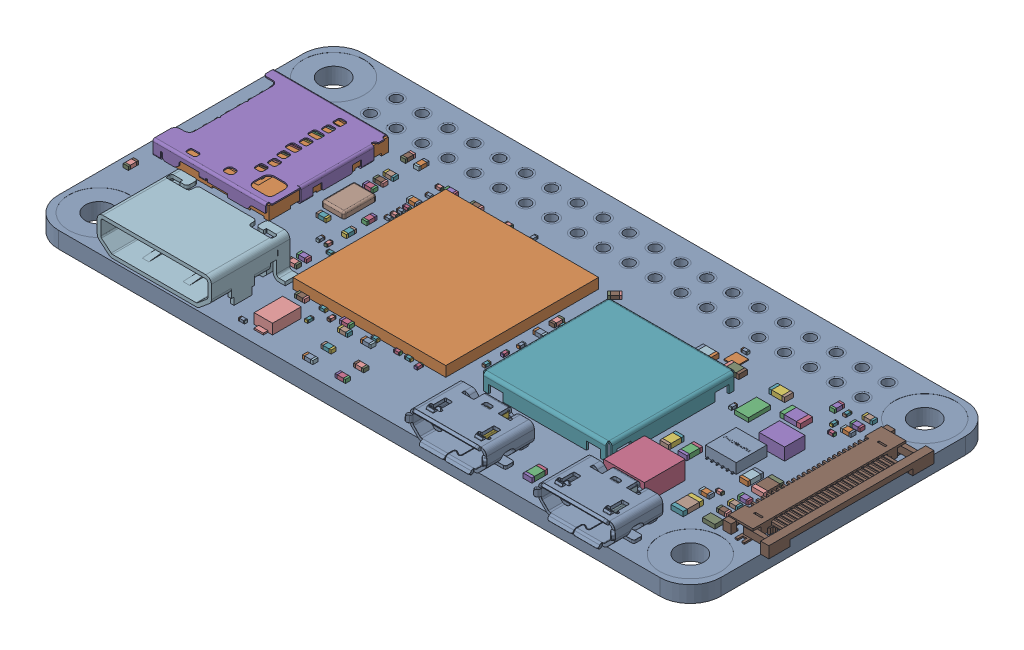
SolidWorks assembly Raspberry Pi Zero 2 W, configuration 默认. Lengths in mm.
Overall size (65.8 5.05 30.58).
93 component instances, 21 part files, 0 mates.
Components (placement in the parent):
- PCB, Raspberry Pi Zero 2 W-1: PCB, Raspberry Pi Zero 2 W [默认] at origin size (65 1.6 30)
- RP3A0-AU 2105 201221C, Raspberry Pi Zero 2 W-1: RP3A0-AU 2105 201221C, Raspberry Pi Zero 2 W [默认] at (-5.5 0.8 1) size (15 1 15)
- MicroUSB Port, Raspberry Pi Zero 2 W-1: MicroUSB Port, Raspberry Pi Zero 2 W [默认] at (8.9 0.8 13) size (7.99 2.94 5.43)
- SD Card Slot, Raspberry Pi Zero 2 W-1: SD Card Slot, Raspberry Pi Zero 2 W [默认] at (-25.5 0.8 -2) x (0 0 1) z (-1 0 0) size (11.95 1.45 11.4)
- Wireless Module Cover, Raspberry Pi Zero 2 W-1: Wireless Module Cover, Raspberry Pi Zero 2 W [默认] at (11 0.8 1.5) size (12.6 1.6 12.6)
- Crystal Resonator, Raspberry Pi Zero 2 W-1: Crystal Resonator, Raspberry Pi Zero 2 W [默认] at (-17.5 0.8 -1.5) size (2.2 0.6 3.2)
- LED, Raspberry Pi Zero 2 W-1: LED, Raspberry Pi Zero 2 W [默认] at (27.5 0.8 7.8) size (1.2 0.4 0.8)
- Diode, Schottky, Raspberry Pi Zero 2 W-1: Diode, Schottky, Raspberry Pi Zero 2 W [默认] at (-11 0.8 12) size (1.8 1 3.7)
- 54548-2271, 22 Pin FPC Connector, Raspberry Pi Zero 2 W-1: 54548-2271, 22 Pin FPC Connector, Raspberry Pi Zero 2 W [默认] at (28.75 0.82 0) x (0 0 -1) z (1 0 0) size (16.2 1.2 5)
- Mini HDMI Receptacle Port, Raspberry Pi Zero 2 W-1: Mini HDMI Receptacle Port, Raspberry Pi Zero 2 W [默认] at (-20.1 2.65 15) size (12.9 4.05 7.7)
- PAM2306AYPKE, Switching Voltage Regulators Dual PWM Step-Down 40uA 1A_ 1.5MHz, Raspberry Pi Zero 2 W-1: PAM2306AYPKE, Switching Voltage Regulators Dual PWM Step-Down 40uA 1A_ 1.5MHz, Raspberry Pi Zero 2 W [默认] at (23 0.8 1) x (0 0 1) z (-1 0 0) size (3.4 1 3)
- RT9081A-1BGQZA, Fixed LDO Voltage Regulator, 0.8V-5.5Vin, 140mV drop,_ 1.25Vout, 0.5Aout, Raspberry Pi Zero 2 W_default-1: RT9081A-1BGQZA, Fixed LDO Voltage Regulator, 0.8V-5.5Vin, 140mV drop,_ 1.25Vout, 0.5Aout, Raspberry Pi Zero 2 W_default [默认] at (14.8 0.8 -7.2) size (1.2 0.1 1.2)
- RT8088AWSC, IC Reg Buck Prog 3A Sync 15WLCSP, Raspberry Pi Zero 2 W_d_efault-1: RT8088AWSC, IC Reg Buck Prog 3A Sync 15WLCSP, Raspberry Pi Zero 2 W_d_efault [默认] at (20 0.8 -3.6) size (1.36 0.4 2.16)
- SMD Inductor, Configurable, Raspberry Pi Zero 2 W_L1-1: SMD Inductor, Configurable, Raspberry Pi Zero 2 W_L1 [默认] at (20.5 0.8 7.5) size (4 1.8 4)
- SMD Inductor, Configurable, Raspberry Pi Zero 2 W_L2-1: SMD Inductor, Configurable, Raspberry Pi Zero 2 W_L2 [默认] at (24.5 0.8 -2) size (2.5 1.2 2)
- SMD Capacitor, Configurable, Raspberry Pi Zero 2 W_C1-1: SMD Capacitor, Configurable, Raspberry Pi Zero 2 W_C1 [默认] at (24.9 0.8 7.7) size (1.2 0.45 2)
- MicroUSB Port, Raspberry Pi Zero 2 W-2: MicroUSB Port, Raspberry Pi Zero 2 W [默认] at (21.5 0.8 13) size (7.99 2.94 5.43)
- SMD Capacitor, Configurable, Raspberry Pi Zero 2 W_C3-1: SMD Capacitor, Configurable, Raspberry Pi Zero 2 W_C3 [默认] at (20.5 0.8 3) size (0.85 0.45 1.55)
- SMD Capacitor, Configurable, Raspberry Pi Zero 2 W_C3-2: SMD Capacitor, Configurable, Raspberry Pi Zero 2 W_C3 [默认] at (18.7 0.8 3) size (0.85 0.45 1.55)
- SMD Capacitor, Configurable, Raspberry Pi Zero 2 W_C1-2: SMD Capacitor, Configurable, Raspberry Pi Zero 2 W_C1 [默认] at (27.3 0.8 2.2) size (1.2 0.45 2)
- SMD Capacitor, Configurable, Raspberry Pi Zero 2 W_C3-3: SMD Capacitor, Configurable, Raspberry Pi Zero 2 W_C3 [默认] at (25.7 0.8 2.2) size (0.85 0.45 1.55)
- SMD Capacitor, Configurable, Raspberry Pi Zero 2 W_C1-3: SMD Capacitor, Configurable, Raspberry Pi Zero 2 W_C1 [默认] at (22.8 0.8 -5.1) x (0 0 -1) z (1 0 0) size (1.2 0.45 2)
- SMD Capacitor, Configurable, Raspberry Pi Zero 2 W_C3-4: SMD Capacitor, Configurable, Raspberry Pi Zero 2 W_C3 [默认] at (20 0.8 -6.4) x (0 0 -1) z (1 0 0) size (0.85 0.45 1.55)
- SMD Capacitor, Configurable, Raspberry Pi Zero 2 W_C3-5: SMD Capacitor, Configurable, Raspberry Pi Zero 2 W_C3 [默认] at (15.8 0.8 -6.1) x (0 0 -1) z (1 0 0) size (0.85 0.45 1.55)
- SMD Capacitor, Configurable, Raspberry Pi Zero 2 W_C3-6: SMD Capacitor, Configurable, Raspberry Pi Zero 2 W_C3 [默认] at (13 0.8 -6.1) x (0 0 -1) z (1 0 0) size (0.85 0.45 1.55)
- SMD Capacitor, Configurable, Raspberry Pi Zero 2 W_C3-7: SMD Capacitor, Configurable, Raspberry Pi Zero 2 W_C3 [默认] at (14.8 0.8 12.5) size (0.85 0.45 1.55)
- SMD Capacitor, Configurable, Raspberry Pi Zero 2 W_C2-1: SMD Capacitor, Configurable, Raspberry Pi Zero 2 W_C2 [默认] at (-9.5 0.8 10.4) size (0.3 0.25 0.6)
- SMD Capacitor, Configurable, Raspberry Pi Zero 2 W_C10-1: SMD Capacitor, Configurable, Raspberry Pi Zero 2 W_C10 [默认] at (-31.4 0.8 6) size (0.5 0.35 1)
- SMD Capacitor, Configurable, Raspberry Pi Zero 2 W_C10-2: SMD Capacitor, Configurable, Raspberry Pi Zero 2 W_C10 [默认] at (-6.1 0.8 13.7) x (0 0 -1) z (1 0 0) size (0.5 0.35 1)
- SMD Capacitor, Configurable, Raspberry Pi Zero 2 W_C10-3: SMD Capacitor, Configurable, Raspberry Pi Zero 2 W_C10 [默认] at (-2.9 0.8 13.7) x (0 0 -1) z (1 0 0) size (0.5 0.35 1)
- SMD Capacitor, Configurable, Raspberry Pi Zero 2 W_C10-4: SMD Capacitor, Configurable, Raspberry Pi Zero 2 W_C10 [默认] at (-6.1 0.8 11.9) x (0 0 -1) z (1 0 0) size (0.5 0.35 1)
- SMD Capacitor, Configurable, Raspberry Pi Zero 2 W_C10-5: SMD Capacitor, Configurable, Raspberry Pi Zero 2 W_C10 [默认] at (-2.9 0.8 11.9) x (0 0 -1) z (1 0 0) size (0.5 0.35 1)
- SMD Capacitor, Configurable, Raspberry Pi Zero 2 W_C10-6: SMD Capacitor, Configurable, Raspberry Pi Zero 2 W_C10 [默认] at (-4.6 0.8 9.5) x (0 0 -1) z (1 0 0) size (0.5 0.35 1)
- SMD Capacitor, Configurable, Raspberry Pi Zero 2 W_C10-7: SMD Capacitor, Configurable, Raspberry Pi Zero 2 W_C10 [默认] at (-7.3 0.8 8.9) x (0 0 -1) z (1 0 0) size (0.5 0.35 1)
- SMD Capacitor, Configurable, Raspberry Pi Zero 2 W_C2-2: SMD Capacitor, Configurable, Raspberry Pi Zero 2 W_C2 [默认] at (-4.6 0.8 8.8) x (0 0 -1) z (1 0 0) size (0.3 0.25 0.6)
- SMD Capacitor, Configurable, Raspberry Pi Zero 2 W_C10-8: SMD Capacitor, Configurable, Raspberry Pi Zero 2 W_C10 [默认] at (2.9 0.8 -1.5) x (-1 0 0) z (0 0 -1) size (0.5 0.35 1)
- SMD Capacitor, Configurable, Raspberry Pi Zero 2 W_C10-9: SMD Capacitor, Configurable, Raspberry Pi Zero 2 W_C10 [默认] at (3.1 0.8 0.3) x (0 0 -1) z (1 0 0) size (0.5 0.35 1)
- SMD Capacitor, Configurable, Raspberry Pi Zero 2 W_C2-3: SMD Capacitor, Configurable, Raspberry Pi Zero 2 W_C2 [默认] at (-2.4 0.8 8.8) x (0 0 -1) z (1 0 0) size (0.3 0.25 0.6)
- SMD Capacitor, Configurable, Raspberry Pi Zero 2 W_C2-4: SMD Capacitor, Configurable, Raspberry Pi Zero 2 W_C2 [默认] at (-9.7 0.8 8.8) x (0 0 -1) z (1 0 0) size (0.3 0.25 0.6)
- SMD Capacitor, Configurable, Raspberry Pi Zero 2 W_C2-5: SMD Capacitor, Configurable, Raspberry Pi Zero 2 W_C2 [默认] at (-8.5 0.8 9.2) x (-1 0 0) z (0 0 -1) size (0.3 0.25 0.6)
- SMD Capacitor, Configurable, Raspberry Pi Zero 2 W_C2-6: SMD Capacitor, Configurable, Raspberry Pi Zero 2 W_C2 [默认] at (3.1 0.8 2.2) x (-1 0 0) z (0 0 -1) size (0.3 0.25 0.6)
- SMD Capacitor, Configurable, Raspberry Pi Zero 2 W_C2-7: SMD Capacitor, Configurable, Raspberry Pi Zero 2 W_C2 [默认] at (3 0.8 3.7) x (-1 0 0) z (0 0 -1) size (0.3 0.25 0.6)
- SMD Capacitor, Configurable, Raspberry Pi Zero 2 W_C2-8: SMD Capacitor, Configurable, Raspberry Pi Zero 2 W_C2 [默认] at (3 0.8 5.5) x (-1 0 0) z (0 0 -1) size (0.3 0.25 0.6)
- SMD Capacitor, Configurable, Raspberry Pi Zero 2 W_C10-10: SMD Capacitor, Configurable, Raspberry Pi Zero 2 W_C10 [默认] at (-27.8 0.8 7.8) x (0 0 -1) z (1 0 0) size (0.5 0.35 1)
- SMD Capacitor, Configurable, Raspberry Pi Zero 2 W_C2-9: SMD Capacitor, Configurable, Raspberry Pi Zero 2 W_C2 [默认] at (-12.7 0.8 13.7) x (0 0 -1) z (1 0 0) size (0.3 0.25 0.6)
- SMD Capacitor, Configurable, Raspberry Pi Zero 2 W_C10-11: SMD Capacitor, Configurable, Raspberry Pi Zero 2 W_C10 [默认] at (-17.7 0.8 -3.8) x (0 0 -1) z (1 0 0) size (0.5 0.35 1)
- SMD Capacitor, Configurable, Raspberry Pi Zero 2 W_C10-12: SMD Capacitor, Configurable, Raspberry Pi Zero 2 W_C10 [默认] at (-17.5 0.8 1) x (0 0 -1) z (1 0 0) size (0.5 0.35 1)
- SMD Capacitor, Configurable, Raspberry Pi Zero 2 W_C2-10: SMD Capacitor, Configurable, Raspberry Pi Zero 2 W_C2 [默认] at (-7.7 0.8 -7.4) x (0 0 -1) z (1 0 0) size (0.3 0.25 0.6)
- SMD Capacitor, Configurable, Raspberry Pi Zero 2 W_C2-11: SMD Capacitor, Configurable, Raspberry Pi Zero 2 W_C2 [默认] at (-5.4 0.8 -7.5) x (-1 0 0) z (0 0 -1) size (0.3 0.25 0.6)
- SMD Capacitor, Configurable, Raspberry Pi Zero 2 W_C2-12: SMD Capacitor, Configurable, Raspberry Pi Zero 2 W_C2 [默认] at (-0.15 0.8 9) x (-1 0 0) z (0 0 -1) size (0.3 0.25 0.6)
- SMD Capacitor, Configurable, Raspberry Pi Zero 2 W_C2-13: SMD Capacitor, Configurable, Raspberry Pi Zero 2 W_C2 [默认] at (-1.3 0.8 8.8) x (0 0 -1) z (1 0 0) size (0.3 0.25 0.6)
- SMD Capacitor, Configurable, Raspberry Pi Zero 2 W_C10-13: SMD Capacitor, Configurable, Raspberry Pi Zero 2 W_C10 [默认] at (-15 0.8 6.4) x (0 0 -1) z (1 0 0) size (0.5 0.35 1)
- SMD Capacitor, Configurable, Raspberry Pi Zero 2 W_C2-14: SMD Capacitor, Configurable, Raspberry Pi Zero 2 W_C2 [默认] at (-14.2 0.8 -2.1) x (0 0 -1) z (1 0 0) size (0.3 0.25 0.6)
- SMD Capacitor, Configurable, Raspberry Pi Zero 2 W_C10-14: SMD Capacitor, Configurable, Raspberry Pi Zero 2 W_C10 [默认] at (-15 0.8 -1) size (0.5 0.35 1)
- SMD Capacitor, Configurable, Raspberry Pi Zero 2 W_C10-15: SMD Capacitor, Configurable, Raspberry Pi Zero 2 W_C10 [默认] at (-14.9 0.8 1.1) size (0.5 0.35 1)
- SMD Capacitor, Configurable, Raspberry Pi Zero 2 W_C2-15: SMD Capacitor, Configurable, Raspberry Pi Zero 2 W_C2 [默认] at (-14.3 0.8 -7.2) x (0 0 -1) z (1 0 0) size (0.3 0.25 0.6)
- SMD Capacitor, Configurable, Raspberry Pi Zero 2 W_C2-16: SMD Capacitor, Configurable, Raspberry Pi Zero 2 W_C2 [默认] at (-14.1 0.8 -6) x (0 0 -1) z (1 0 0) size (0.3 0.25 0.6)
- SMD Capacitor, Configurable, Raspberry Pi Zero 2 W_C2-17: SMD Capacitor, Configurable, Raspberry Pi Zero 2 W_C2 [默认] at (-13.3 0.8 1.7) size (0.3 0.25 0.6)
- SMD Capacitor, Configurable, Raspberry Pi Zero 2 W_C2-18: SMD Capacitor, Configurable, Raspberry Pi Zero 2 W_C2 [默认] at (-13.3 0.8 -0.9) size (0.3 0.25 0.6)
- SMD Capacitor, Configurable, Raspberry Pi Zero 2 W_C2-19: SMD Capacitor, Configurable, Raspberry Pi Zero 2 W_C2 [默认] at (-14.2 0.8 -2.7) x (0 0 -1) z (1 0 0) size (0.3 0.25 0.6)
- SMD Capacitor, Configurable, Raspberry Pi Zero 2 W_C2-20: SMD Capacitor, Configurable, Raspberry Pi Zero 2 W_C2 [默认] at (-14.2 0.8 -3.3) x (0 0 -1) z (1 0 0) size (0.3 0.25 0.6)
- SMD Capacitor, Configurable, Raspberry Pi Zero 2 W_C2-21: SMD Capacitor, Configurable, Raspberry Pi Zero 2 W_C2 [默认] at (-14.2 0.8 -3.9) x (0 0 -1) z (1 0 0) size (0.3 0.25 0.6)
- SMD Capacitor, Configurable, Raspberry Pi Zero 2 W_C2-22: SMD Capacitor, Configurable, Raspberry Pi Zero 2 W_C2 [默认] at (-14.1 0.8 3.7) x (0 0 -1) z (1 0 0) size (0.3 0.25 0.6)
- SMD Capacitor, Configurable, Raspberry Pi Zero 2 W_C2-23: SMD Capacitor, Configurable, Raspberry Pi Zero 2 W_C2 [默认] at (-15 0.8 3) size (0.3 0.25 0.6)
- SMD Capacitor, Configurable, Raspberry Pi Zero 2 W_C2-24: SMD Capacitor, Configurable, Raspberry Pi Zero 2 W_C2 [默认] at (-15.8 0.8 3) size (0.3 0.25 0.6)
- SMD Capacitor, Configurable, Raspberry Pi Zero 2 W_C2-25: SMD Capacitor, Configurable, Raspberry Pi Zero 2 W_C2 [默认] at (25.8 0.8 -5.6) x (0 0 -1) z (1 0 0) size (0.3 0.25 0.6)
- SMD Capacitor, Configurable, Raspberry Pi Zero 2 W_C2-26: SMD Capacitor, Configurable, Raspberry Pi Zero 2 W_C2 [默认] at (25.1 0.8 -6.5) size (0.3 0.25 0.6)
- SMD Capacitor, Configurable, Raspberry Pi Zero 2 W_C2-27: SMD Capacitor, Configurable, Raspberry Pi Zero 2 W_C2 [默认] at (25.3 0.8 4.9) x (0 0 -1) z (1 0 0) size (0.3 0.25 0.6)
- SMD Capacitor, Configurable, Raspberry Pi Zero 2 W_C2-28: SMD Capacitor, Configurable, Raspberry Pi Zero 2 W_C2 [默认] at (18.7 0.8 -3) size (0.3 0.25 0.6)
- SMD Capacitor, Configurable, Raspberry Pi Zero 2 W_C2-29: SMD Capacitor, Configurable, Raspberry Pi Zero 2 W_C2 [默认] at (6.9269 0.8 8.9) x (0 0 -1) z (1 0 0) size (0.3 0.25 0.6)
- SMD Capacitor, Configurable, Raspberry Pi Zero 2 W_C2-30: SMD Capacitor, Configurable, Raspberry Pi Zero 2 W_C2 [默认] at (3.5 0.8 -1.5) x (-1 0 0) z (0 0 -1) size (0.3 0.25 0.6)
- SMD Resistor, Configurable, Raspberry Pi Zero 2 W_R1-1: SMD Resistor, Configurable, Raspberry Pi Zero 2 W_R1 [默认] at (-18.4 0.8 -8.2) size (0.5 0.35 1)
- SMD Resistor, Configurable, Raspberry Pi Zero 2 W_R1-2: SMD Resistor, Configurable, Raspberry Pi Zero 2 W_R1 [默认] at (-17.1 0.8 -8.2) size (0.5 0.35 1)
- SMD Resistor, Configurable, Raspberry Pi Zero 2 W_R1-3: SMD Resistor, Configurable, Raspberry Pi Zero 2 W_R1 [默认] at (23.9 0.8 -8) size (0.5 0.35 1)
- SMD Resistor, Configurable, Raspberry Pi Zero 2 W_R12-1: SMD Resistor, Configurable, Raspberry Pi Zero 2 W_R12 [默认] at (24.9 0.8 -8) size (0.3 0.23 0.6)
- SMD Resistor, Configurable, Raspberry Pi Zero 2 W_R1-4: SMD Resistor, Configurable, Raspberry Pi Zero 2 W_R1 [默认] at (-10.8 0.8 -7.3) x (0 0 1) z (-1 0 0) size (0.5 0.35 1)
- SMD Resistor, Configurable, Raspberry Pi Zero 2 W_R1-5: SMD Resistor, Configurable, Raspberry Pi Zero 2 W_R1 [默认] at (-14.3 0.8 -4.7) x (0 0 1) z (-1 0 0) size (0.5 0.35 1)
- SMD Resistor, Configurable, Raspberry Pi Zero 2 W_R1-6: SMD Resistor, Configurable, Raspberry Pi Zero 2 W_R1 [默认] at (-13.3 0.8 -7.3) x (0 0 1) z (-1 0 0) size (0.5 0.35 1)
- SMD Resistor, Configurable, Raspberry Pi Zero 2 W_R1-7: SMD Resistor, Configurable, Raspberry Pi Zero 2 W_R1 [默认] at (-17.7 0.8 -5.8) x (0 0 1) z (-1 0 0) size (0.5 0.35 1)
- SMD Resistor, Configurable, Raspberry Pi Zero 2 W_R1-8: SMD Resistor, Configurable, Raspberry Pi Zero 2 W_R1 [默认] at (-17.7 0.8 -4.8) x (0 0 1) z (-1 0 0) size (0.5 0.35 1)
- SMD Resistor, Configurable, Raspberry Pi Zero 2 W_R1-9: SMD Resistor, Configurable, Raspberry Pi Zero 2 W_R1 [默认] at (-27.7 0.8 4.8) x (0 0 1) z (-1 0 0) size (0.5 0.35 1)
- SMD Resistor, Configurable, Raspberry Pi Zero 2 W_R1-10: SMD Resistor, Configurable, Raspberry Pi Zero 2 W_R1 [默认] at (-15 0.8 5.4) x (0 0 1) z (-1 0 0) size (0.5 0.35 1)
- SMD Resistor, Configurable, Raspberry Pi Zero 2 W_R1-11: SMD Resistor, Configurable, Raspberry Pi Zero 2 W_R1 [默认] at (-6.7 0.8 9.6958) x (0 0 1) z (-1 0 0) size (0.5 0.35 1)
- SMD Resistor, Configurable, Raspberry Pi Zero 2 W_R1-12: SMD Resistor, Configurable, Raspberry Pi Zero 2 W_R1 [默认] at (-11.7 0.8 8.9) x (0 0 1) z (-1 0 0) size (0.5 0.35 1)
- SMD Resistor, Configurable, Raspberry Pi Zero 2 W_R1-13: SMD Resistor, Configurable, Raspberry Pi Zero 2 W_R1 [默认] at (24.8 0.8 5.7) x (0 0 1) z (-1 0 0) size (0.5 0.35 1)
- SMD Resistor, Configurable, Raspberry Pi Zero 2 W_R1-14: SMD Resistor, Configurable, Raspberry Pi Zero 2 W_R1 [默认] at (27.2 0.8 4.3) x (0 0 1) z (-1 0 0) size (0.5 0.35 1)
- SMD Resistor, Configurable, Raspberry Pi Zero 2 W_R1-15: SMD Resistor, Configurable, Raspberry Pi Zero 2 W_R1 [默认] at (27.2 0.8 5.3) x (0 0 1) z (-1 0 0) size (0.5 0.35 1)
- SMD Resistor, Configurable, Raspberry Pi Zero 2 W_R1-16: SMD Resistor, Configurable, Raspberry Pi Zero 2 W_R1 [默认] at (27.2 0.8 6.4) x (0 0 1) z (-1 0 0) size (0.5 0.35 1)
- SMD Resistor, Configurable, Raspberry Pi Zero 2 W_R1-17: SMD Resistor, Configurable, Raspberry Pi Zero 2 W_R1 [默认] at (26.5 0.8 -6.5) x (0 0 1) z (-1 0 0) size (0.5 0.35 1)
- SMD Resistor, Configurable, Raspberry Pi Zero 2 W_R1-18: SMD Resistor, Configurable, Raspberry Pi Zero 2 W_R1 [默认] at (26.5 0.8 -7.4) x (0 0 1) z (-1 0 0) size (0.5 0.35 1)
- SMD Resistor, Configurable, Raspberry Pi Zero 2 W_R1-19: SMD Resistor, Configurable, Raspberry Pi Zero 2 W_R1 [默认] at (26.5 0.8 -8.6) x (0 0 1) z (-1 0 0) size (0.5 0.35 1)
- SMD Resistor, Configurable, Raspberry Pi Zero 2 W_R1-20: SMD Resistor, Configurable, Raspberry Pi Zero 2 W_R1 [默认] at (3.5 0.8 -6.6) x (0.707107 0 0.707107) z (-0.707107 0 0.707107) size (0.5 0.35 1)
- SMD Capacitor, Configurable, Raspberry Pi Zero 2 W_C2-31: SMD Capacitor, Configurable, Raspberry Pi Zero 2 W_C2 [默认] at (14.6 0.8 -8.3) x (0 0 -1) z (1 0 0) size (0.3 0.25 0.6)
